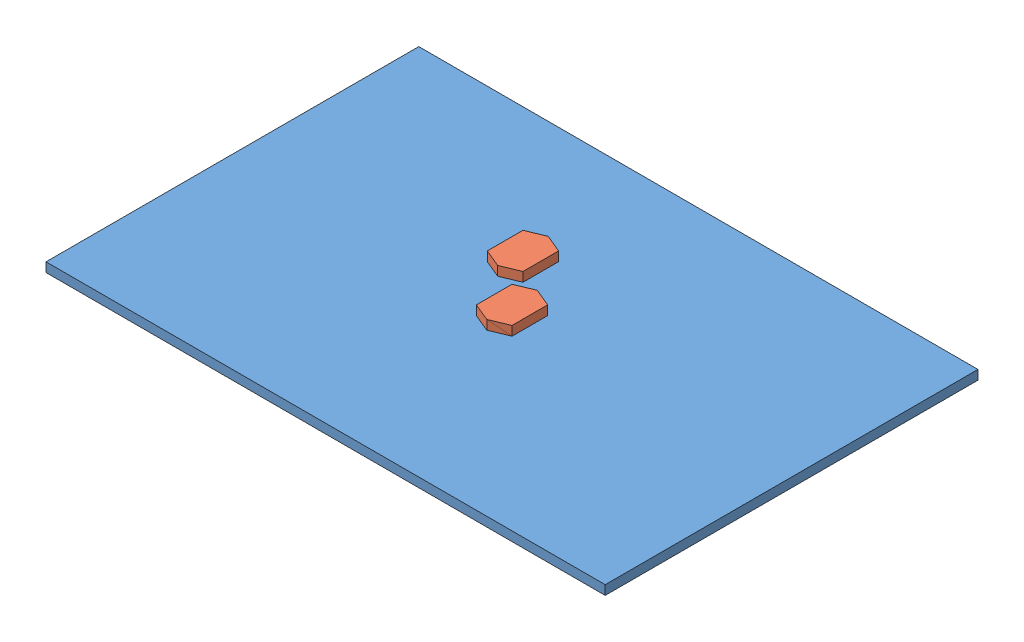
SolidWorks assembly two_node_6750, configuration Default. Lengths in mm.
Overall size (600 25 400).
3 component instances, 2 part files, 6 mates.
Components (placement in the parent):
- ground-1: ground [Default] at origin size (600 10 400)
- node_6750-1: node_6750 [Default] at origin size (38.27 10 54.12)
- node_6750-2: node_6750 [Default] at (-39.2611 5 -51.007) size (38.27 10 54.12)
Mates (geometry in assembly coordinates):
- Coincident2: coincident aligned: plane of ground-1 through (0 0 0) normal (0 1 0)
- Coincident3: coincident aligned: plane of ground-1 through (0 0 0) normal (1 0 0)
- Coincident4: coincident aligned: plane of ground-1 through (0 0 0) normal (0 0 1)
- Coincident5: coincident aligned: plane of node_6750-1 through (0 0 0) normal (0 0 1)
- Coincident6: coincident aligned: plane of node_6750-1 through (0 0 0) normal (0 1 0)
- Coincident7: coincident aligned: plane of node_6750-1 through (0 0 0) normal (1 0 0)
